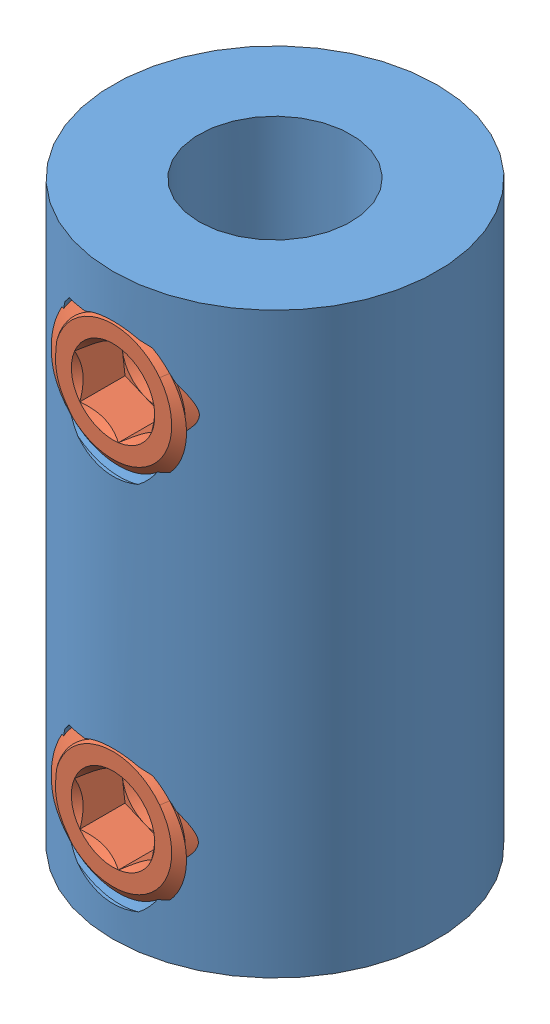
SolidWorks assembly Motor coupler, configuration Default. Lengths in mm.
Overall size (10.67 19.11 10.81).
3 component instances, 2 part files, 0 mates.
Components (placement in the parent):
- 625120-1: 625120 [Default] at (-58.4931 -1.3175 25.2523) size (10.67 19.05 10.73)
- 632134_91375A436-1: 632134_91375A436 [Default] at (-58.4931 14.3035 29.3961) x (0.606109 -0.795381 0) z (0 0 1) size (4.98 4.83 3.31)
- 632134_91375A436-2: 632134_91375A436 [Default] at (-58.4931 2.1115 29.3961) x (0.605824 -0.795599 0) z (0 0 1) size (4.98 4.83 3.31)
